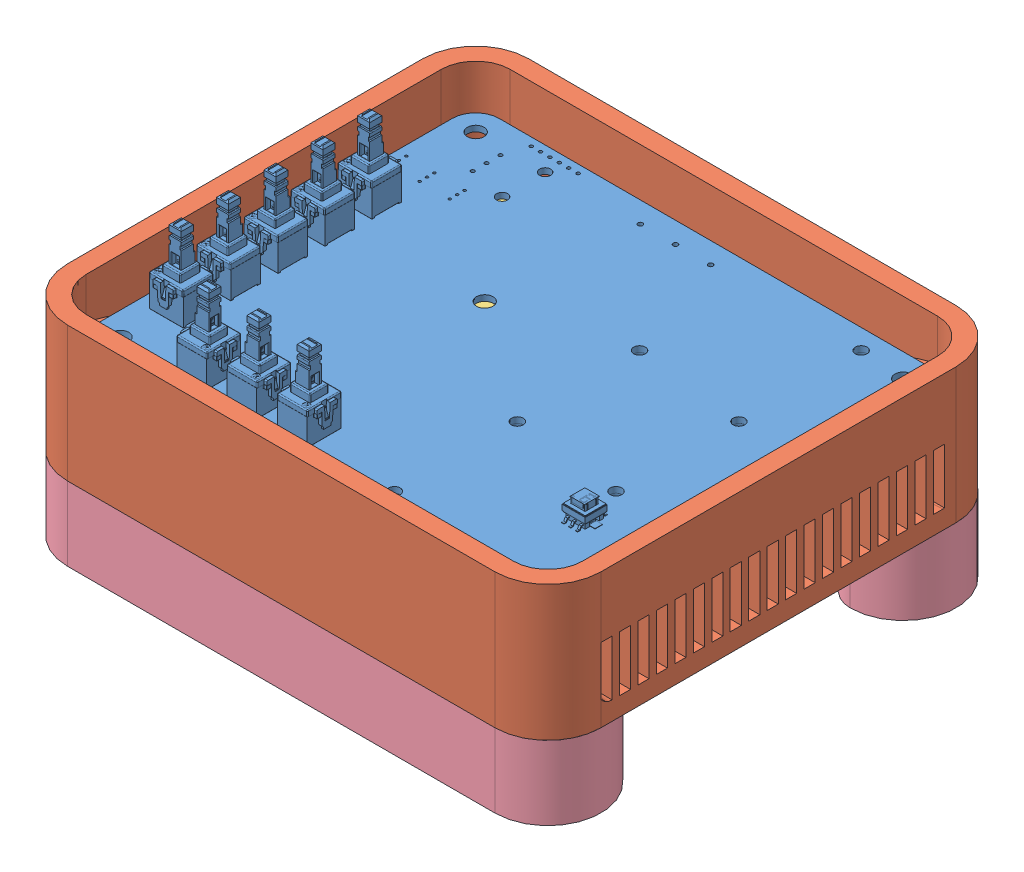
SolidWorks assembly Enclosure Assembly, configuration Default(1). Lengths in mm.
Overall size (144.82 67.5 124.86).
5 component instances, 4 part files, 13 mates.
Components (placement in the parent):
- InverterPCB-1: InverterPCB [Default] at (-5.1624 23.8297 147.2707) x (1 0 0) z (0 1 0)
- Enclosure Bottom-1: Enclosure Bottom [Default] at (0 1891.2462 -7.6626)
- BFB0512L (1)-3: BFB0512L (1) [Default] at (46.2919 9.3651 94.1978) x (0 0 1) z (-1 0 0)
- BFB0512L (1)-4: BFB0512L (1) [Default] at (46.2919 9.3651 40.1356) x (0 0 1) z (-1 0 0)
- Part1-1: Part1 [Default] at (0 -2.7349 -7.6626) x (-1 0 0) z (0 -1 0) size (144.82 124.86 20.39)
Mates (geometry in assembly coordinates):
- Parallel2: parallel anti-aligned: plane of InverterPCB-1 through (-5.1624 22.2651 140.9207) normal (0 -1 0); plane of assembly through (0 0 0) normal (0 1 0)
- Parallel4: parallel aligned: plane of InverterPCB-1 through (1.1876 22.2651 147.2707) normal (0 0 1); plane of assembly through (0 0 0) normal (0 0 1)
- Coincident7: coincident aligned: plane of BFB0512L (1)-3 through (46.7919 10.3194 114.2878) normal (1 0 0); plane of BFB0512L (1)-4 through (46.7919 10.3194 60.2256) normal (1 0 0)
- Parallel7: parallel aligned: plane of Enclosure Bottom-1 through (-8.1624 234.7452 -7.6626) normal (1 0 0); plane of BFB0512L (1)-3 through (46.7919 10.3194 114.2878) normal (1 0 0)
- Coincident9: coincident aligned: plane of BFB0512L (1)-3 through (20.2098 2.2651 121.9153) normal (0 -1 0); plane of BFB0512L (1)-4 through (20.2098 2.2651 67.853) normal (0 -1 0)
- Coincident10: coincident anti-aligned: plane of Enclosure Bottom-1 through (116.9109 2.2651 140.9219) normal (0 1 0); plane of BFB0512L (1)-3 through (20.2098 2.2651 121.9153) normal (0 -1 0)
- Concentric3: concentric anti-aligned: cylinder of InverterPCB-1 through (1.1876 22.2651 44.7563) axis (0 -1 0) radius 2.25; cylinder of BFB0512L (1)-4 through (1.1876 10.3194 44.7563) axis (0 1 0) radius 2.2601
- Coincident11: coincident aligned: plane of Enclosure Bottom-1 through (0 1891.2462 -7.6626) normal (1 0 0); plane of assembly through (0 0 0) normal (1 0 0)
- Distance3: distance = 2 mm anti-aligned: plane of BFB0512L (1)-3 through (34.6731 11.1651 93.4153) normal (0 0 -1); cylinder of BFB0512L (1)-4 through (39.3586 10.3194 87.9498) axis (0 1 0) radius 3.4655
- InPlace1: in place: plane of Enclosure Bottom-1 through (116.9109 -2.7349 140.9219) normal (0 -1 0); plane of ? through (0 -2.7349 0) normal (0 -1 0); moOrthogonalPlaneRef_w of Enclosure Bottom-1 through (116.9109 -2.7349 140.9219) normal (0 -1 0); unknown of ?; plane of Enclosure Bottom-1 through (116.9109 -2.7349 140.9219) normal (0 -1 0); line of ? through (-55 0 -2.7349) axis (0 -1 0); plane of Enclosure Bottom-1 through (116.9109 -2.7349 140.9219) normal (0 -1 0); unknown of Part1-1
- Coincident12: coincident aligned: plane of Enclosure Bottom-1; plane of Part1-1
- Coincident13: coincident aligned: moOrthogonalPlaneRef_w of Enclosure Bottom-1 through (0 -2.7349 -7.6626) normal (0 0 -1); plane of Part1-1
- Coincident14: coincident anti-aligned: moOrthogonalPlaneRef_w of Enclosure Bottom-1 through (0 -2.7349 -7.6626) normal (1 0 0); plane of Part1-1
